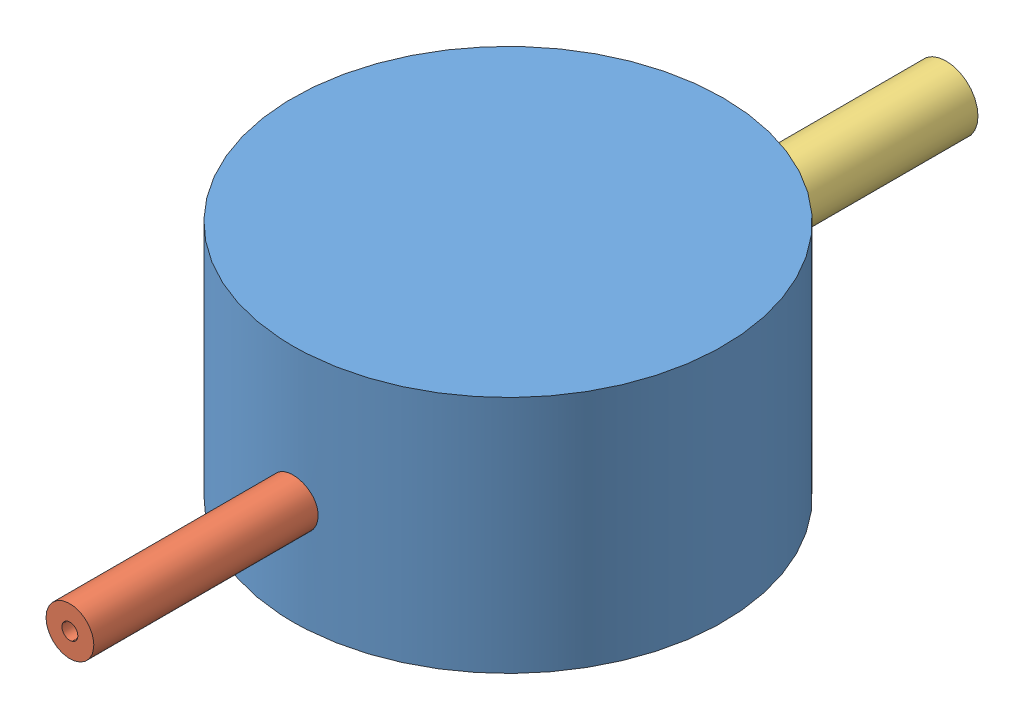
SolidWorks assembly 3Dview-Top, configuration Default. Lengths in mm.
Overall size (27 15 55).
3 component instances, 3 part files, 4 mates.
Components (placement in the parent):
- Top-1: Top [Default] at origin size (27 15 27)
- 3x1-1: 3x1 [Default] at (0 6.5 7.5) x (0.999962 0.00877 0) z (0 0 1) size (3 3 20)
- 4x2-1: 4x2 [Default] at (0 8 -27.5) size (4 4 20)
Mates (geometry in assembly coordinates):
- Concentrico1: concentric aligned: circle of Top-1; circle of 3x1-1
- Coincidente1: coincident: line of Top-1 through (0 5 7.5) axis (0 -1 0); plane of 3x1-1 through (0 6.5 7.5) normal (0 0 -1)
- Concentrico2: concentric: circle of Top-1; circle of 4x2-1
- Coincidente5: coincident: line of Top-1 through (0 6 -7.5) axis (0 -1 0); plane of 4x2-1 through (0 8 -7.5) normal (0 0 1)
